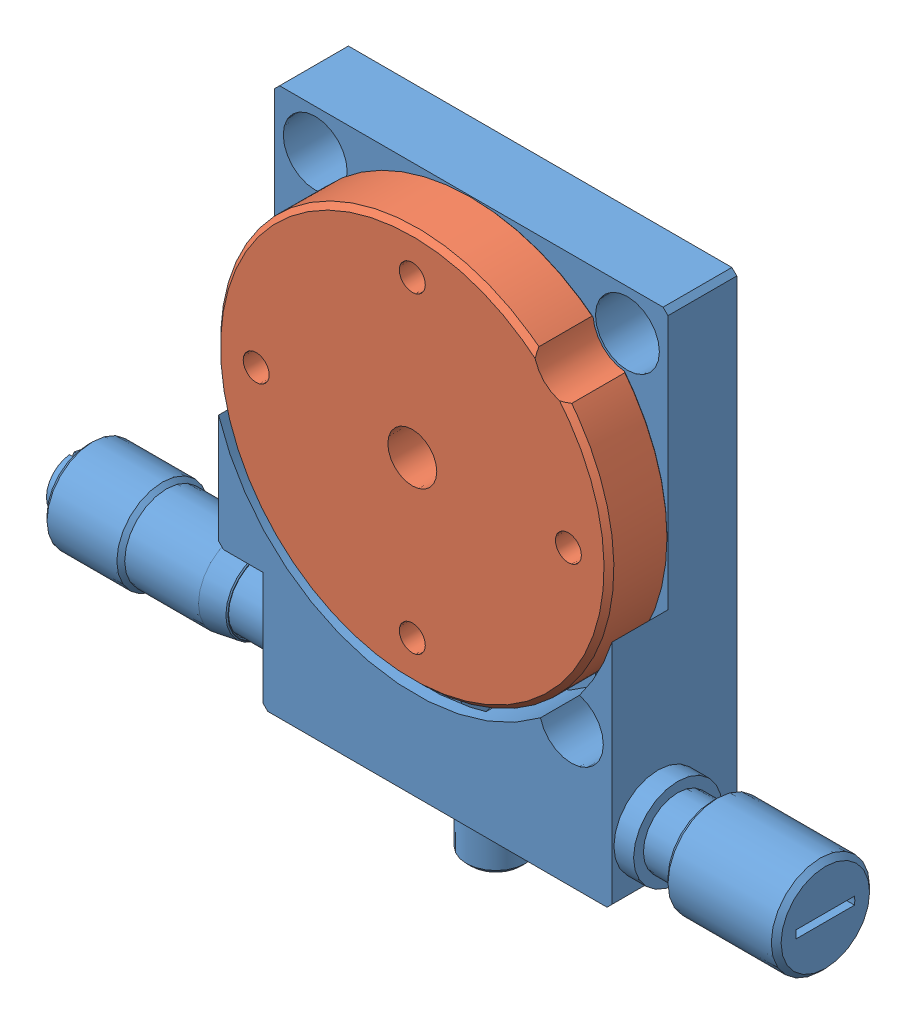
SolidWorks assembly Rotation_stage_124-0030, configuration Default. Lengths in mm.
Overall size (77.52 59 13).
2 component instances, 2 part files, 0 mates.
Components (placement in the parent):
- KSP-40UU-C1A-S05-1: KSP-40UU-C1A-S05 [Default] at origin size (77.52 59 13)
- KSP-40UU-C1A-S01-1: KSP-40UU-C1A-S01 [Default] at (0 0 13) x (0 -1 0) z (0 0 1) size (40 40 11.5)
